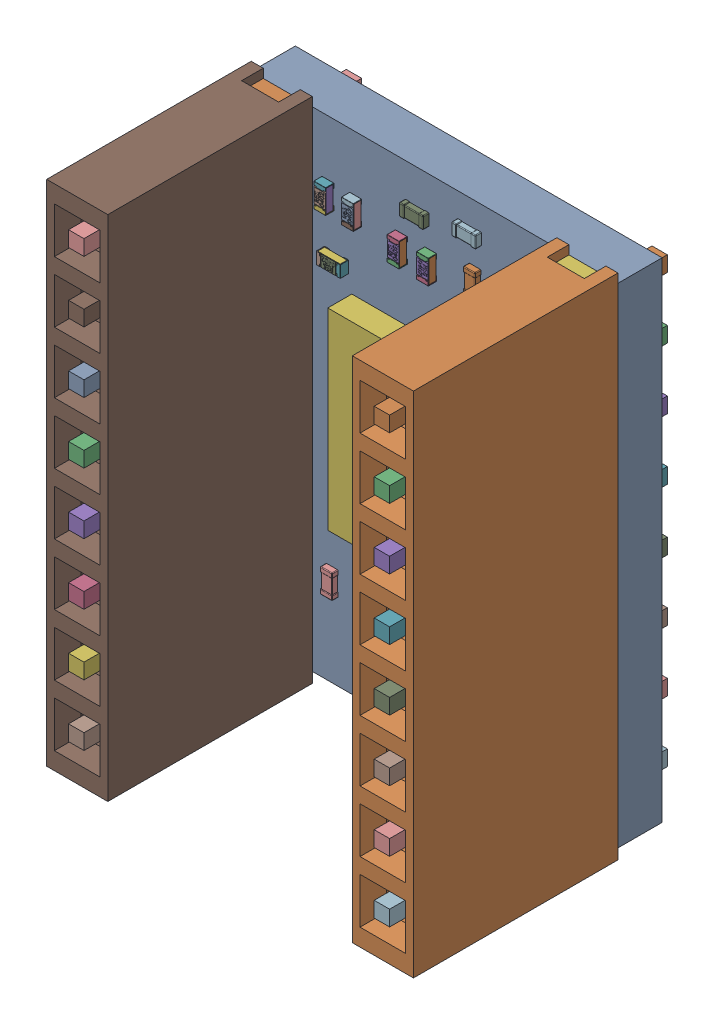
SolidWorks assembly PCB-2, configuration 默认. Lengths in mm.
Overall size (15.24 21.12 11.54).
81 component instances, 15 part files, 0 mates.
Components (placement in the parent):
- Board-2-1: Board-2 [默认] at origin size (15.24 20.32 1.83)
  - Open CASCADE STEP translator 6.8 2.1.1-1: Open CASCADE STEP translator 6.8 2.1.1 [默认] at (0 0 -1.8339) size (15.24 20.32 1.83)
- X-1: X [默认] at origin size (15.24 21.12 11.5)
  - DS1023-1x8SF11-1: DS1023-1x8SF11 [默认] at (13.9593 19.0061 0) x (0 -1 0) z (0 0 1) size (21.12 2.54 11.5)
  - DS1023-1x8SF11-2: DS1023-1x8SF11 [默认] at (1.2593 19.0061 0) x (0 -1 0) z (0 0 1) size (21.12 2.54 11.5)
- U5-1: U5 [默认] at origin size (3.17 3.19 0.82)
  - 6641442208-1: 6641442208 [默认] at (8.4975 4.6 -2.7339) size (3.17 3.19 0.81)
    - Extruded-19-1: Extruded-19 [默认] at origin size (3.17 3.19 0.81)
  - 6641441808-1: 6641441808 [默认] at (7.1852 5.8608 -2.7339) x (0 -1 0) z (0 0 -1) size (0.2 0.2 0.01)
    - Cylinder-20-1: Cylinder-20 [默认] at origin size (0.2 0.2 0.01)
- U1-1: U1 [默认] at origin size (3.19 3.17 0.82)
  - 6641441568-1: 6641441568 [默认] at (6.25 17.0875 -2.7339) size (3.19 3.17 0.81)
    - Extruded-21-1: Extruded-21 [默认] at origin size (3.19 3.17 0.81)
  - 6641441328-1: 6641441328 [默认] at (7.5108 18.3998 -2.7339) x (-1 0 0) z (0 0 -1) size (0.2 0.2 0.01)
    - Cylinder-22-1: Cylinder-22 [默认] at origin size (0.2 0.2 0.01)
- C8-1: C8 [默认] at origin size (0.5 1 0.5)
  - User_Library-C0402-1-1: User_Library-C0402-1 [默认] at (11.385 3.6234 -1.8339) x (0 -1 0) z (0 0 -1) size (1 0.5 0.5)
- R9-1: R9 [默认] at origin size (0.5 1 0.35)
  - User_Library-User_Library-RES0402-2-1: User_Library-User_Library-RES0402-2 [默认] at (3.9988 13.3623 -1.8339) x (0 1 0) z (0 0 -1) size (1 0.5 0.35)
- R1-1: R1 [默认] at origin size (0.5 1 0.35)
  - User_Library-User_Library-RES0402-2-1: User_Library-User_Library-RES0402-2 [默认] at (3.1812 17.5123 0) x (0 1 0) z (0 0 1) size (1 0.5 0.35)
- C3-1: C3 [默认] at origin size (0.5 1 0.5)
  - User_Library-C0402-1-1: User_Library-C0402-1 [默认] at (11.895 11.6466 -1.8339) x (0 1 0) z (0 0 -1) size (1 0.5 0.5)
- U4-1: U4 [默认] at origin size (3.17 3.19 0.82)
  - 6641442208-1: 6641442208 [默认] at (4.4325 4.57 -2.7339) size (3.17 3.19 0.81)
    - Extruded-19-1: Extruded-19 [默认] at origin size (3.17 3.19 0.81)
  - 6641440128-1: 6641440128 [默认] at (5.7448 3.3092 -2.7339) x (0 1 0) z (0 0 -1) size (0.2 0.2 0.01)
    - Cylinder-23-1: Cylinder-23 [默认] at origin size (0.2 0.2 0.01)
- U3-1: U3 [默认] at origin size (3.19 3.17 0.82)
  - 6641441328-1: 6641441328 [默认] at (12.1608 18.3998 -2.7339) x (-1 0 0) z (0 0 -1) size (0.2 0.2 0.01)
    - Cylinder-22-1: Cylinder-22 [默认] at origin size (0.2 0.2 0.01)
  - 6641441568-1: 6641441568 [默认] at (10.9 17.0875 -2.7339) size (3.19 3.17 0.81)
    - Extruded-21-1: Extruded-21 [默认] at origin size (3.19 3.17 0.81)
- C1-1: C1 [默认] at origin size (0.5 1 0.5)
  - User_Library-C0402-1-1: User_Library-C0402-1 [默认] at (9.535 17.4466 0) x (0 1 0) z (0 0 1) size (1 0.5 0.5)
- C2-1: C2 [默认] at origin size (1 0.5 0.5)
  - User_Library-C0402-1-1: User_Library-C0402-1 [默认] at (10.4533 16.155 0) x (-1 0 0) z (0 0 1) size (1 0.5 0.5)
- C4-1: C4 [默认] at origin size (1 0.5 0.5)
  - User_Library-C0402-1-1: User_Library-C0402-1 [默认] at (7.7766 4.515 0) x (1 0 0) z (0 0 1) size (1 0.5 0.5)
- C5-1: C5 [默认] at origin size (1 0.5 0.5)
  - User_Library-C0402-1-1: User_Library-C0402-1 [默认] at (11.2534 3.655 0) x (-1 0 0) z (0 0 1) size (1 0.5 0.5)
- C7-1: C7 [默认] at origin size (0.81 1.6 0.8)
  - 6641443168-1: 6641443168 [默认] at (12.3314 3.3249 -2.6339) size (0.8 0.23 0.8)
    - Extruded-24-1: Extruded-24 [默认] at origin size (0.8 0.23 0.8)
  - 6641443168-2: 6641443168 [默认] at (12.3314 4.6949 -2.6339) size (0.8 0.23 0.8)
    - Extruded-24-1: Extruded-24 [默认] at origin size (0.8 0.23 0.8)
  - 6641442768-1: 6641442768 [默认] at (12.3313 4.0099 -2.6339) size (0.8 1.14 0.8)
    - Extruded-25-1: Extruded-25 [默认] at origin size (0.8 1.14 0.8)
- C11-1: C11 [默认] at origin size (1 0.5 0.5)
  - User_Library-C0402-1-1: User_Library-C0402-1 [默认] at (6.8766 18.415 0) x (1 0 0) z (0 0 1) size (1 0.5 0.5)
- C12-1: C12 [默认] at origin size (0.5 1 0.5)
  - User_Library-C0402-1-1: User_Library-C0402-1 [默认] at (3.095 3.6734 0) x (0 -1 0) z (0 0 1) size (1 0.5 0.5)
- C13-1: C13 [默认] at origin size (0.5 1 0.5)
  - User_Library-C0402-1-1: User_Library-C0402-1 [默认] at (4.235 11.2234 -1.8339) x (0 -1 0) z (0 0 -1) size (1 0.5 0.5)
- C14-1: C14 [默认] at origin size (0.5 1 0.5)
  - User_Library-C0402-1-1: User_Library-C0402-1 [默认] at (11.895 9.1466 -1.8339) x (0 1 0) z (0 0 -1) size (1 0.5 0.5)
- C15-1: C15 [默认] at origin size (0.5 1 0.5)
  - User_Library-C0402-1-1: User_Library-C0402-1 [默认] at (12.485 4.8966 0) x (0 1 0) z (0 0 1) size (1 0.5 0.5)
- J3-1: J3 [默认] at origin size (2.54 20.32 11.54)
  - 1001-8-1: 1001-8 [默认] at (1.259 19.037 0) x (0 -1 0) z (0 0 1) size (20.32 2.54 11.54)
- J4-1: J4 [默认] at origin size (2.54 20.32 11.54)
  - 1001-8-1: 1001-8 [默认] at (13.959 19.037 0) x (0 -1 0) z (0 0 1) size (20.32 2.54 11.54)
- R2-1: R2 [默认] at origin size (1.25 2 0.5)
  - User_Library-R_0805-1: User_Library-R_0805 [默认] at (3.19 17.0633 -1.8239) x (0 1 0) z (0 0 -1) size (2 1.25 0.5)
- R3-1: R3 [默认] at origin size (0.5 1 0.35)
  - User_Library-User_Library-RES0402-2-1: User_Library-User_Library-RES0402-2 [默认] at (7.4488 17.1077 0) x (0 -1 0) z (0 0 1) size (1 0.5 0.35)
- R4-1: R4 [默认] at origin size (1 0.5 0.35)
  - User_Library-User_Library-RES0402-2-1: User_Library-User_Library-RES0402-2 [默认] at (3.5377 15.3012 0) x (-1 0 0) z (0 0 1) size (1 0.5 0.35)
- R6-1: R6 [默认] at origin size (0.5 1 0.35)
  - User_Library-User_Library-RES0402-2-1: User_Library-User_Library-RES0402-2 [默认] at (4.3312 17.5123 0) x (0 1 0) z (0 0 1) size (1 0.5 0.35)
- R8-1: R8 [默认] at origin size (0.5 1 0.35)
  - User_Library-User_Library-RES0402-2-1: User_Library-User_Library-RES0402-2 [默认] at (6.2312 17.1123 0) x (0 1 0) z (0 0 1) size (1 0.5 0.35)
- U2-1: U2 [默认] at origin size (8 8 1)
  - 6641437328-1: 6641437328 [默认] at (8.169 10.388 0) size (8 8 1)
    - Extruded-26-1: Extruded-26 [默认] at origin size (8 8 1)
  - 6641437008-1: 6641437008 [默认] at (11.439 13.736 0) x (0 -1 0) z (0 0 1) size (0.4 0.4 1)
    - Cylinder-27-1: Cylinder-27 [默认] at origin size (0.4 0.4 1)
- R7-1: R7 [默认] at origin size (1.25 2 0.5)
  - User_Library-R_0805-1: User_Library-R_0805 [默认] at (3.74 8.4067 -1.8239) x (0 -1 0) z (0 0 -1) size (2 1.25 0.5)
- C10-1: C10 [默认] at origin size (1 0.5 0.5)
  - User_Library-C0402-1-1: User_Library-C0402-1 [默认] at (9.0534 19.305 0) x (-1 0 0) z (0 0 1) size (1 0.5 0.5)
